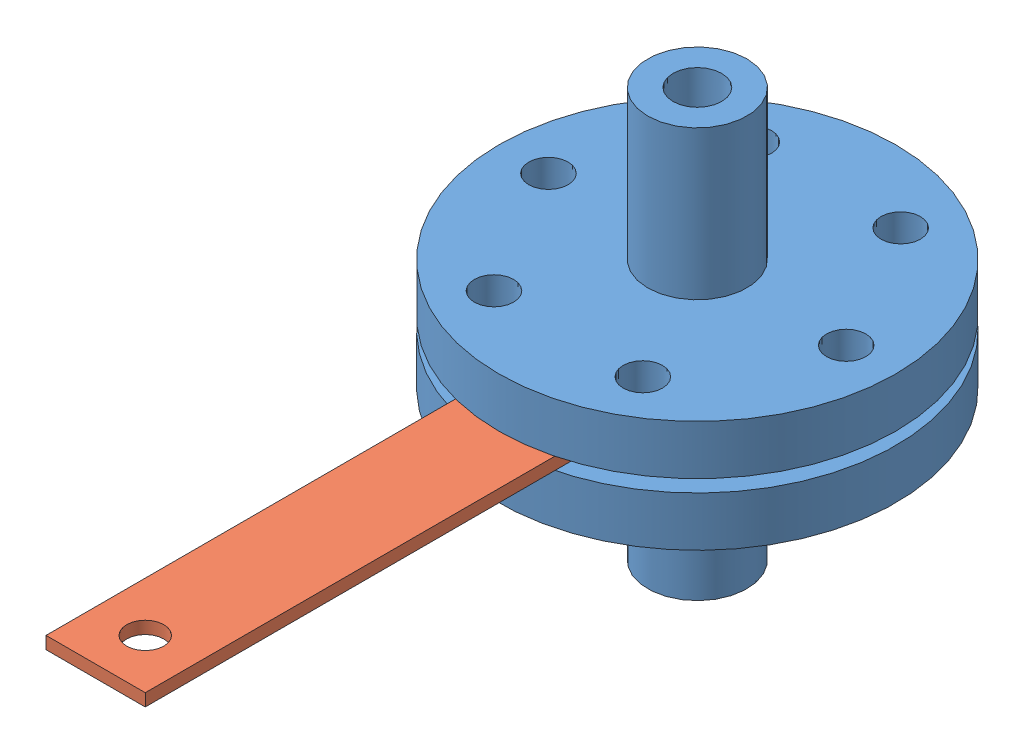
SolidWorks assembly orifice_flow_meter, configuration Default. Lengths in mm.
Overall size (138.79 104.77 223.38).
3 component instances, 2 part files, 7 mates.
Components (placement in the parent):
- orifice_flow_meter_flange-1: orifice_flow_meter_flange [Default] at origin size (101.6 50.8 101.6)
- 2206N11_Flange-Mount Flow-Control Orifice-1: 2206N11_Flange-Mount Flow-Control Orifice [2206N11] at (0 -52.3875 0) x (1 0 0) z (0 -1 0) size (53.98 180.97 3.17)
- orifice_flow_meter_flange-2: orifice_flow_meter_flange [Default] at (0 -104.775 0) x (0.5 0 -0.866025) z (-0.866025 0 -0.5) size (101.6 50.8 101.6)
Mates (geometry in assembly coordinates):
- Concentric1: concentric aligned: cylinder of orifice_flow_meter_flange-1 through (0 -50.8 0) axis (0 -1 0) radius 50.8; cylinder of 2206N11_Flange-Mount Flow-Control Orifice-1 through (0 -50.8 0) axis (0 -1 0) radius 26.9875
- Coincident1: coincident anti-aligned: plane of orifice_flow_meter_flange-1 through (-50.8 -50.8 0) normal (0 -1 0); plane of 2206N11_Flange-Mount Flow-Control Orifice-1 through (13.208 -50.8 24.9807) normal (0 1 0)
- Coincident2: coordinate: point of orifice_flow_meter_flange-1
- Concentric2: concentric anti-aligned: cylinder of orifice_flow_meter_flange-1 through (0 -50.8 0) axis (0 -1 0) radius 50.8; cylinder of orifice_flow_meter_flange-2 through (0 -53.975 0) axis (0 1 0) radius 50.8
- Coincident4: coincident anti-aligned: plane of 2206N11_Flange-Mount Flow-Control Orifice-1 through (13.208 -53.975 24.9807) normal (0 -1 0); plane of orifice_flow_meter_flange-2 through (-25.4 -53.975 43.9941) normal (0 1 0)
- Parallel1: parallel aligned: plane of 2206N11_Flange-Mount Flow-Control Orifice-1 through (12.7 -50.8 153.9875) normal (1 0 0)
- Concentric4: concentric anti-aligned: cylinder of orifice_flow_meter_flange-1 through (-19.05 -38.1 32.9956) axis (0 1 0) radius 5.0419; cylinder of orifice_flow_meter_flange-2 through (-19.05 -66.675 32.9956) axis (0 -1 0) radius 5.0419
